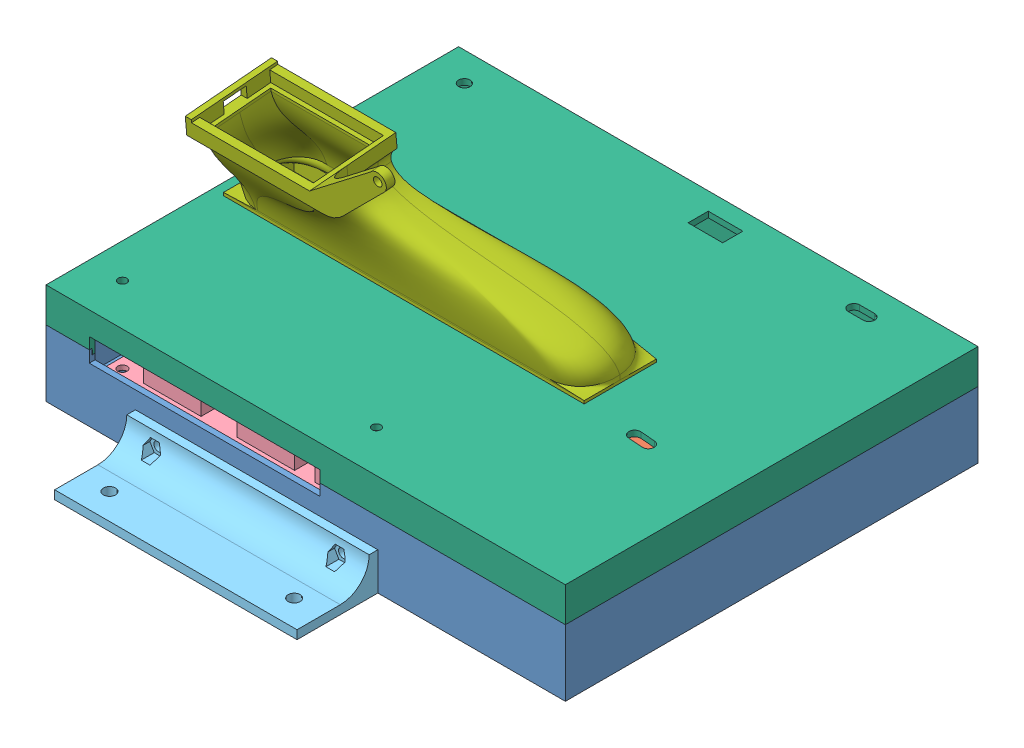
SolidWorks assembly MKSboard with ByeByeBoard, configuration Default. Lengths in mm.
Overall size (208 93.81 171).
7 component instances, 7 part files, 19 mates.
Components (placement in the parent):
- BottomWithByeByeBoard-1: BottomWithByeByeBoard [Default] at (63.9824 87.8835 143.9681) size (180 23 143)
- MKS v1.3 Board-1: MKS v1.3 Board [Default] at (63.9824 94.8835 143.9681) x (-1 0 0) z (0 0 -1) size (143 20.7 84)
- ShortMountRigidbotOriginal-1: ShortMountRigidbotOriginal [Default] at (-29.5176 90.8835 178.9681) x (0 0 -1) z (0 -1 0) size (58 28 13)
- ByeByeBoard-1: ByeByeBoard [Default] at (22.4824 94.8835 212.4681) size (95 11.6 25)
- LongMountRigidbotOriginal-1: LongMountRigidbotOriginal [Default] at (57.4824 90.8835 252.9681) x (-1 0 0) z (0 -1 0) size (84 28 13)
- LidWithByeByeBoard-1: LidWithByeByeBoard [Default] at (74.4824 120.8835 167.4681) size (180 14 143)
- RadialFanDuct-1: RadialFanDuct [Default] at (50.9824 117.8835 168.9681) size (126.51 63.81 58.87)
Mates (geometry in assembly coordinates):
- Coincident1: coincident anti-aligned: plane of BottomWithByeByeBoard-1 through (-15.5176 90.8835 95.9681) normal (-1 0 0); plane of ShortMountRigidbotOriginal-1 through (-15.5176 87.8835 207.9681) normal (1 0 0)
- Concentric1: concentric anti-aligned: cylinder of BottomWithByeByeBoard-1 through (-8.9921 95.8835 159.9681) axis (-1 0 0) radius 1.6; cylinder of ShortMountRigidbotOriginal-1 through (-18.5176 95.8835 159.9681) axis (1 0 0) radius 1.6
- Concentric2: concentric anti-aligned: cylinder of BottomWithByeByeBoard-1 through (-8.9921 95.8835 197.9681) axis (-1 0 0) radius 1.6; cylinder of ShortMountRigidbotOriginal-1 through (-18.5176 95.8835 197.9681) axis (1 0 0) radius 1.6
- Coincident3: coincident anti-aligned: plane of BottomWithByeByeBoard-1 through (-15.5176 90.8835 238.9681) normal (0 0 1); plane of LongMountRigidbotOriginal-1 through (99.4824 87.8835 238.9681) normal (0 0 -1)
- Concentric4: concentric anti-aligned: cylinder of BottomWithByeByeBoard-1 through (25.4824 95.8835 232.4426) axis (0 0 1) radius 1.6; cylinder of LongMountRigidbotOriginal-1 through (25.4824 95.8835 241.9681) axis (0 0 -1) radius 1.6
- Concentric5: concentric anti-aligned: cylinder of BottomWithByeByeBoard-1 through (89.4824 95.8835 232.4426) axis (0 0 1) radius 1.6; cylinder of LongMountRigidbotOriginal-1 through (89.4824 95.8835 241.9681) axis (0 0 -1) radius 1.6
- Coincident4: coincident anti-aligned: plane of BottomWithByeByeBoard-1 through (-3.5176 94.8835 105.9681) normal (0 1 0); plane of MKS v1.3 Board-1 through (63.9824 94.8835 143.9681) normal (0 -1 0)
- Concentric6: concentric aligned: cylinder of BottomWithByeByeBoard-1 through (-3.5176 90.8835 105.9681) axis (0 -1 0) radius 2; cylinder of MKS v1.3 Board-1 through (-3.5176 96.5835 105.9681) axis (0 -1 0) radius 2
- Parallel2: parallel aligned: cylinder of BottomWithByeByeBoard-1 through (-3.5176 90.8835 182.3681) axis (0 -1 0) radius 2; cylinder of MKS v1.3 Board-1 through (-3.5176 96.5835 181.9681) axis (0 -1 0) radius 2
- Width1: width anti-aligned: plane of BottomWithByeByeBoard-1 through (131.4824 90.8835 103.9681) normal (0 0 1); plane of BottomWithByeByeBoard-1 through (131.4824 90.8835 107.9681) normal (0 0 -1); cylinder of MKS v1.3 Board-1 through (131.4824 96.5835 105.9681) axis (0 -1 0) radius 2
- Coincident6: coincident anti-aligned: plane of BottomWithByeByeBoard-1 through (84.4824 94.8835 224.4681) normal (0 1 0); plane of ByeByeBoard-1 through (22.4824 94.8835 212.4681) normal (0 -1 0)
- Concentric8: concentric aligned: cylinder of BottomWithByeByeBoard-1 through (84.4824 94.8835 224.4681) axis (0 -1 0) radius 1.5; cylinder of ByeByeBoard-1 through (84.4824 96.4835 224.4681) axis (0 -1 0) radius 1.6
- Concentric9: concentric aligned: cylinder of BottomWithByeByeBoard-1 through (-3.5176 94.8835 224.4681) axis (0 -1 0) radius 1.5; cylinder of ByeByeBoard-1 through (-3.5176 96.4835 224.4681) axis (0 -1 0) radius 1.6
- Coincident7: coincident anti-aligned: plane of BottomWithByeByeBoard-1 through (63.9824 110.8835 143.9681) normal (0 1 0); plane of LidWithByeByeBoard-1 through (74.4824 110.8835 167.4681) normal (0 -1 0)
- Coincident8: coincident aligned: plane of BottomWithByeByeBoard-1 through (164.4824 90.8835 238.9681) normal (1 0 0); plane of LidWithByeByeBoard-1 through (164.4824 122.8835 95.9681) normal (1 0 0)
- Coincident9: coincident aligned: plane of BottomWithByeByeBoard-1 through (-15.5176 90.8835 238.9681) normal (0 0 1); plane of LidWithByeByeBoard-1 through (-15.5176 122.8835 238.9681) normal (0 0 1)
- Width3: width anti-aligned: plane of RadialFanDuct-1 through (-11.5176 122.8835 180.9681) normal (0 0 1); plane of RadialFanDuct-1 through (-11.5176 122.8835 156.9681) normal (0 0 -1); plane of LidWithByeByeBoard-1 through (113.4824 -6.3997 180.9681) normal (0 0 -1); plane of LidWithByeByeBoard-1 through (113.4824 -6.3997 156.9681) normal (0 0 1)
- Width4: width anti-aligned: plane of RadialFanDuct-1 through (113.4824 119.8835 156.4681) normal (1 0 0); plane of RadialFanDuct-1 through (-11.5176 119.8835 156.4681) normal (-1 0 0); plane of LidWithByeByeBoard-1 through (113.4824 -6.3997 180.9681) normal (-1 0 0); plane of LidWithByeByeBoard-1 through (-11.5176 -6.3997 180.9681) normal (1 0 0)
- Coincident10: coincident anti-aligned: plane of LidWithByeByeBoard-1 through (74.4824 122.8835 167.4681) normal (0 1 0); plane of RadialFanDuct-1 through (50.9824 122.8835 168.9681) normal (0 -1 0)
